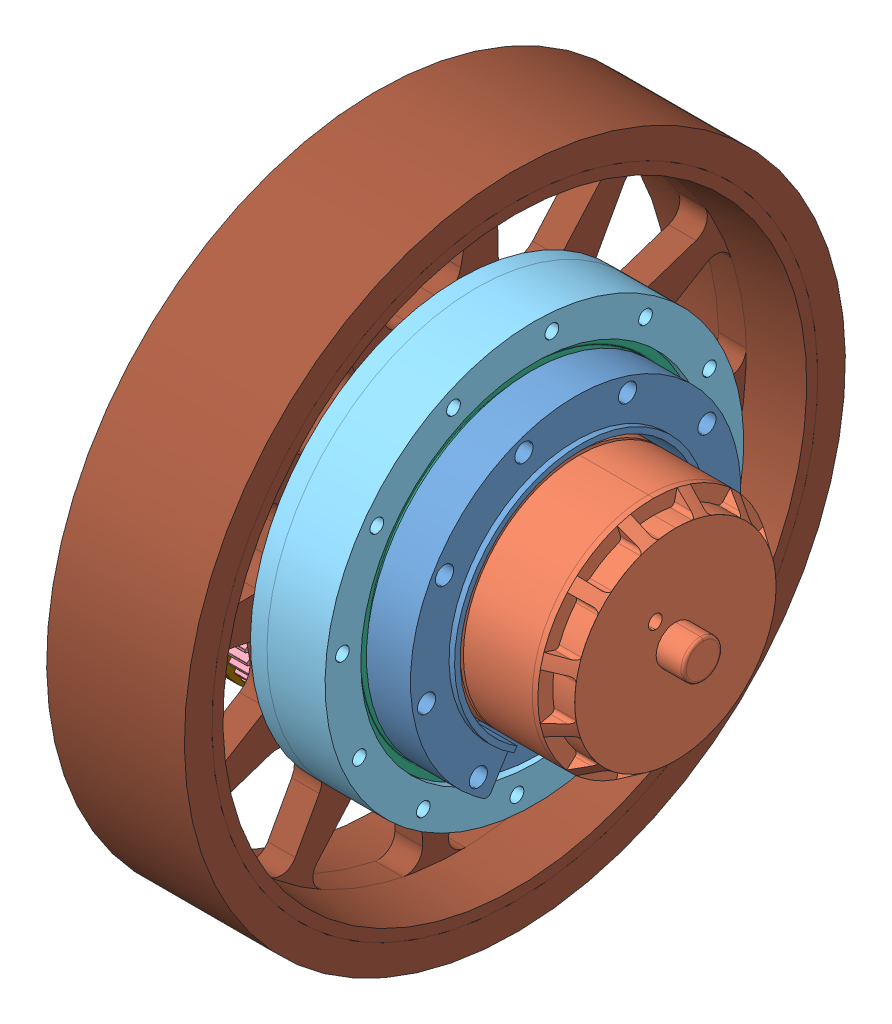
SolidWorks assembly OB ASM改, configuration 默认. Lengths in mm.
Overall size (62.1 167.23 167.23).
25 component instances, 11 part files, 67 mates.
Components (placement in the parent):
- M01改-1: M01改 [默认] at (-15.2454 0 0) x (-1 0 0) z (0 1 0) size (37 60 60)
- RoboMaster M3508改-1: RoboMaster M3508改 [默认] at (23.1956 -8.7166 -16.154) x (0 -0.922142 0.386852) z (-1 0 0) size (42 44.97 43.4)
- GEAR01改-1: GEAR01改 [默认] at (-50.0454 0 0) x (0 0.247551 -0.968875) z (1 0 0) size (10.24 10.24 22.5)
- GEAR02改-1: GEAR02改 [默认] at (-49.2454 18.15 0) x (0 0.099251 -0.995062) z (1 0 0) size (28.69 28.68 13)
- GEAR03改-1: GEAR03改 [默认] at (-44.2954 0 0) x (0 -0.817182 0.576379) z (1 0 0) size (76 76 21.55)
- GEAR02改-2: GEAR02改 [默认] at (-49.2454 -9.075 15.7184) x (0 0.812124 0.583485) z (1 0 0) size (28.69 28.68 13)
- GEAR02改-3: GEAR02改 [默认] at (-49.2454 -9.075 -15.7184) x (0 -0.911375 0.411577) z (1 0 0) size (28.69 28.68 13)
- RA5008改-1: RA5008改 [默认] at (-32.2454 0 0) x (0 0.378016 0.925799) z (0 0.925799 -0.378016) size (66 8 66)
- 法兰轴承 4-7-2.5改-1: 法兰轴承 4-7-2.5改 [默认] at (-35.6454 18.15 0) x (0 0.689337 0.724441) z (0 -0.724441 0.689337) size (8.2 2.5 8.2)
- 法兰轴承 4-7-2.5改-5: 法兰轴承 4-7-2.5改 [默认] at (-49.8454 18.15 0) x (0 0.329942 0.944001) z (0 0.944001 -0.329942) size (8.2 2.5 8.2)
- 法兰轴承 4-7-2.5改-3: 法兰轴承 4-7-2.5改 [默认] at (-35.6454 -9.075 15.7184) x (0 -0.972053 0.234763) z (0 -0.234763 -0.972053) size (8.2 2.5 8.2)
- 法兰轴承 4-7-2.5改-4: 法兰轴承 4-7-2.5改 [默认] at (-35.6454 -9.075 -15.7184) x (0 0.282715 -0.959204) z (0 0.959204 0.282715) size (8.2 2.5 8.2)
- 法兰轴承 4-7-2.5改-6: 法兰轴承 4-7-2.5改 [默认] at (-49.8454 -9.075 15.7184) x (0 -0.9825 -0.186263) z (0 -0.186263 0.9825) size (8.2 2.5 8.2)
- 法兰轴承 4-7-2.5改-7: 法兰轴承 4-7-2.5改 [默认] at (-49.8454 -9.075 -15.7184) x (0 0.652558 -0.757738) z (0 -0.757738 -0.652558) size (8.2 2.5 8.2)
- 4-6-0.2不锈钢垫圈改-1: 4-6-0.2不锈钢垫圈改 [默认] at (-35.6454 18.15 0) x (0 0.139017 -0.99029) z (1 0 0) size (6 6 0.2)
- 4-6-0.2不锈钢垫圈改-7: 4-6-0.2不锈钢垫圈改 [默认] at (-50.0454 18.15 0) x (0 0.139017 -0.99029) z (1 0 0) size (6 6 0.2)
- 4-6-0.2不锈钢垫圈改-8: 4-6-0.2不锈钢垫圈改 [默认] at (-50.0454 -9.075 15.7184) x (0 0.788108 0.615537) z (1 0 0) size (6 6 0.2)
- 4-6-0.2不锈钢垫圈改-9: 4-6-0.2不锈钢垫圈改 [默认] at (-50.0454 -9.075 -15.7184) x (0 -0.927125 0.374753) z (1 0 0) size (6 6 0.2)
- 4-6-0.2不锈钢垫圈改-5: 4-6-0.2不锈钢垫圈改 [默认] at (-35.6454 -9.075 15.7184) x (0 0.788108 0.615537) z (1 0 0) size (6 6 0.2)
- 4-6-0.2不锈钢垫圈改-6: 4-6-0.2不锈钢垫圈改 [默认] at (-35.6454 -9.075 -15.7184) x (0 -0.927125 0.374753) z (1 0 0) size (6 6 0.2)
- P01改-1: P01改 [默认] at (-50.2454 0 0) x (0 0 1) z (-1 0 0) size (61.44 57.23 4)
- M02改-1: M02改 [默认] at (-27.2454 18.15 0) x (0 -0.045999 0.998941) z (-1 0 0) size (4 4 26)
- WHEEL改-1: WHEEL改 [步兵] at (-38.7954 0 0) x (1 0 0) z (0 -0.576379 -0.817182) size (25 120 120)
- M02改-2: M02改 [默认] at (-27.2454 -9.075 15.7184) x (0 -0.842109 -0.539307) z (-1 0 0) size (4 4 26)
- M02改-3: M02改 [默认] at (-27.2454 -9.075 -15.7184) x (0 0.888108 -0.459634) z (-1 0 0) size (4 4 26)
Mates (geometry in assembly coordinates):
- 重合1: coincident aligned: plane of M01改-1 through (-15.2454 0 0) normal (0 1 0)
- 重合2: coincident aligned: plane of M01改-1 through (-15.2454 0 0) normal (0 0 1)
- 重合3: coincident anti-aligned: plane of M01改-1 through (-27.2454 0 21.25) normal (1 0 0); plane of RoboMaster M3508-1 through (-27.2454 0 0) normal (-1 0 0)
- 同心1: concentric anti-aligned: cylinder of M01改-1 through (-15.2454 0 0) axis (1 0 0) radius 21.25; cylinder of RoboMaster M3508-1 through (-25.2454 0 0) axis (-1 0 0) radius 21
- 同心2: concentric anti-aligned: cylinder of RoboMaster M3508-1 through (-35.5454 0 0) axis (1 0 0) radius 2.5; cylinder of GEAR01-1 through (-27.5454 0 0) axis (-1 0 0) radius 2.485
- 同心3: concentric aligned: cylinder of M01改-1 through (-14.2454 18.15 0) axis (-1 0 0) radius 2; cylinder of GEAR02-1 through (-36.2454 18.15 0) axis (-1 0 0) radius 3.5
- 距离1: distance = 1 mm anti-aligned: plane of M01改-1 through (-35.2454 18.15 0) normal (-1 0 0); plane of GEAR02-1 through (-36.2454 14.8652 -4.9696) normal (1 0 0)
- 同心4: concentric anti-aligned: cylinder of M01改-1 through (-15.2454 0 0) axis (1 0 0) radius 22.5; cylinder of GEAR03改-1 through (-36.2954 0 0) axis (-1 0 0) radius 27.5
- 齿轮配合1: gear = 12 : 39 mm: cylinder of GEAR02-1 through (-36.2454 18.15 0) axis (-1 0 0) radius 3.5; cylinder of GEAR01-1 through (-27.5454 0 0) axis (-1 0 0) radius 2.485
- 齿轮配合2: gear = 2340 : 168 mm: cylinder of GEAR01-1 through (-27.5454 0 0) axis (-1 0 0) radius 2.485; cylinder of GEAR03改-1 through (-36.2954 0 0) axis (-1 0 0) radius 27.5
- 重合10: coincident anti-aligned: plane of M01改-1 through (-24.2454 0 24.975) normal (-1 0 0); plane of RA5008改-1 through (-24.2454 -10.5089 -25.7372) normal (1 0 0)
- 同心7: concentric anti-aligned: cylinder of M01改-1 through (-15.2454 0 0) axis (1 0 0) radius 24.975; cylinder of RA5008改-1 through (-32.2454 0 0) axis (-1 0 0) radius 25
- 同心8: concentric anti-aligned: cylinder of M01-1 through (-15.2454 0 0) axis (1 0 0) radius 23.525; cylinder of WZ-200-1 through (-32.2954 0 0) axis (-1 0 0) radius 23.345
- 重合11: coincident anti-aligned: plane of M01-1 through (-33.8654 0 23.525) normal (1 0 0); plane of WZ-200-1 through (-33.8654 0 0) normal (-1 0 0)
- 同心9: concentric anti-aligned: cylinder of M01改-1 through (-51.2454 0 -17.5) axis (1 0 0) radius 1.6; cylinder of RoboMaster M3508-1 through (-27.2454 0 -17.5) axis (-1 0 0) radius 1.5
- 重合12: coincident anti-aligned: plane of GEAR02-1 through (-36.2454 14.8652 -4.9696) normal (1 0 0); plane of 法兰轴承 4-7-2.5-1 through (-36.2454 18.15 0) normal (-1 0 0)
- 同心10: concentric anti-aligned: cylinder of GEAR02-1 through (-36.2454 18.15 0) axis (-1 0 0) radius 3.5; cylinder of 法兰轴承 4-7-2.5-1 through (-35.6454 18.15 0) axis (1 0 0) radius 3.5
- 重合13: coincident anti-aligned: plane of GEAR02-1 through (-49.2454 32.4291 1.4243) normal (-1 0 0); plane of 法兰轴承 4-7-2.5-2 through (-49.2454 18.15 0) normal (1 0 0)
- 同心11: concentric aligned: cylinder of GEAR02-1 through (-36.2454 18.15 0) axis (-1 0 0) radius 3.5; cylinder of 法兰轴承 4-7-2.5-2 through (-49.8454 18.15 0) axis (-1 0 0) radius 3.5
- 重合14: coincident anti-aligned: plane of 法兰轴承 4-7-2.5-1 through (-35.6454 18.15 0) normal (1 0 0); plane of 4-6-0.2不锈钢垫圈-1 through (-35.6454 18.15 0) normal (-1 0 0)
- 同心12: concentric anti-aligned: cylinder of 法兰轴承 4-7-2.5-1 through (-35.6454 18.15 0) axis (1 0 0) radius 4.1; cylinder of 4-6-0.2不锈钢垫圈-1 through (-35.4454 18.15 0) axis (-1 0 0) radius 3
- 重合15: coincident anti-aligned: plane of 法兰轴承 4-7-2.5-2 through (-49.8454 18.15 0) normal (-1 0 0); plane of 4-6-0.2不锈钢垫圈-2 through (-49.8454 18.15 0) normal (1 0 0)
- 同心13: concentric aligned: cylinder of 法兰轴承 4-7-2.5-2 through (-49.8454 18.15 0) axis (-1 0 0) radius 2; cylinder of 4-6-0.2不锈钢垫圈-2 through (-49.8454 18.15 0) axis (-1 0 0) radius 2
- 重合16: coincident anti-aligned: plane of M01改-1 through (-50.2454 0 15) normal (-1 0 0); plane of P01改-1 through (-50.2454 0 0) normal (1 0 0)
- 同心15: concentric aligned: cylinder of M01改-1 through (-15.2454 0 0) axis (1 0 0) radius 21.5; cylinder of P01-1 through (-53.2454 0 0) axis (1 0 0) radius 21.5
- 同心16: concentric anti-aligned: cylinder of M01改-1 through (-14.2454 9.5 16.4545) axis (-1 0 0) radius 1.25; cylinder of P01改-1 through (-53.2454 9.5 16.4545) axis (1 0 0) radius 1.6
- 重合17: coincident anti-aligned: plane of 法兰轴承 5-10-4-1 through (-53.2454 0 0) normal (1 0 0); plane of P01改-1 through (-53.2454 0 0) normal (-1 0 0)
- 重合19: coincident anti-aligned: plane of GEAR03改-1 through (-36.2954 -31.0529 21.9024) normal (-1 0 0); plane of WHEEL改-1 through (-36.2954 -42.4935 29.9717) normal (1 0 0)
- 同心19: concentric anti-aligned: cylinder of GEAR03改-1 through (-22.7454 -28.6014 20.1733) axis (-1 0 0) radius 1.6; cylinder of WHEEL改-1 through (-51.2954 -28.6014 20.1733) axis (1 0 0) radius 1.6
- 同心20: concentric anti-aligned: cylinder of GEAR03改-1 through (-44.2954 0 0) axis (-1 0 0) radius 31; cylinder of WHEEL-1 through (-38.7954 0 0) axis (1 0 0) radius 31.05
- 距离3: distance = 8 mm anti-aligned: plane of RoboMaster M3508-1 through (-35.5454 0 0) normal (-1 0 0); plane of GEAR01-1 through (-27.5454 0 0) normal (1 0 0)
- 重合20: coincident anti-aligned: plane of RoboMaster M3508-1 through (-27.2454 0 0) normal (-1 0 0); plane of M02-1 through (-27.2454 18.15 0) normal (1 0 0)
- 同心21: concentric aligned: cylinder of P01改-1 through (-53.2454 18.15 0) axis (1 0 0) radius 2; cylinder of M02-1 through (-53.2454 18.15 0) axis (1 0 0) radius 2
- 重合21: coincident anti-aligned: plane of GEAR03改-1 through (-36.2954 -31.0529 21.9024) normal (-1 0 0); plane of ASM-1/侧板-1 through (-34.5954 29.6416 23.7776) normal (1 0 0)
- 同心22: concentric anti-aligned: cylinder of GEAR03改-1 through (-22.7454 -28.6014 20.1733) axis (-1 0 0) radius 1.25; cylinder of ASM-1/侧板-1 through (-57.0954 32.1511 -12.5123) axis (1 0 0) radius 1.6
- 同心23: concentric aligned: cylinder of GEAR03改-1 through (-44.2954 0 0) axis (-1 0 0) radius 38; cylinder of ASM-1/侧板-1 through (-37.0954 0 0) axis (-1 0 0) radius 38
- 同心24: concentric anti-aligned: cylinder of GEAR01-1 through (-53.5454 0 0) axis (1 0 0) radius 2.5; cylinder of 法兰轴承 5-10-4-1 through (-54.2454 0 0) axis (-1 0 0) radius 2.5
- 重合25: coincident anti-aligned: plane of GEAR03改-1 through (-24.2454 -25.7617 18.1703) normal (-1 0 0); plane of RA5008改-1 through (-24.2454 -12.4745 -30.5514) normal (1 0 0)
- 重合26: coincident anti-aligned: plane of M01改-1 through (-27.2454 0 -21.25) normal (1 0 0); plane of RoboMaster M3508改-1 through (-27.2454 0 0) normal (-1 0 0)
- 同心25: concentric anti-aligned: cylinder of M01改-1 through (-15.2454 0 0) axis (1 0 0) radius 21.25; cylinder of RoboMaster M3508改-1 through (-25.2454 0 0) axis (-1 0 0) radius 21
- 同心26: concentric anti-aligned: cylinder of RoboMaster M3508改-1 through (-35.5454 0 0) axis (1 0 0) radius 2.5; cylinder of GEAR01改-1 through (-27.5454 0 0) axis (-1 0 0) radius 2.485
- 同心27: concentric aligned: cylinder of M01改-1 through (-14.2454 18.15 0) axis (-1 0 0) radius 2; cylinder of GEAR02改-1 through (-36.2454 18.15 0) axis (-1 0 0) radius 3.5
- 距离4: distance = 1 mm anti-aligned: plane of M01改-1 through (-35.2454 18.15 0) normal (-1 0 0); plane of GEAR02改-1 through (-36.2454 14.8652 4.9696) normal (1 0 0)
- 同心28: concentric: cylinder of ? through (-15.2454 0 0) axis (1 0 0) radius 22.5; cylinder of ? through (-36.2954 0 0) axis (-1 0 0) radius 27.5
- 齿轮配合3: gear = 12 : 39 mm: cylinder of GEAR02改-1 through (-36.2454 18.15 0) axis (-1 0 0) radius 3.5; cylinder of GEAR01改-1 through (-27.5454 0 0) axis (-1 0 0) radius 2.485
- 齿轮配合4: gear = 2340 : 168 mm: cylinder of GEAR01改-1 through (-27.5454 0 0) axis (-1 0 0) radius 2.485; cylinder of GEAR03改-1 through (-36.2954 0 0) axis (-1 0 0) radius 27.5
- 重合27: coincident anti-aligned: plane of M01改-1 through (-24.2454 0 -24.975) normal (-1 0 0); plane of RA5008改-1 through (-24.2454 -10.5089 25.7372) normal (1 0 0)
- 同心29: concentric anti-aligned: cylinder of M01改-1 through (-15.2454 0 0) axis (1 0 0) radius 24.975; cylinder of RA5008改-1 through (-32.2454 0 0) axis (-1 0 0) radius 25
- 同心30: concentric anti-aligned: cylinder of M01改-1 through (-51.2454 0 17.5) axis (1 0 0) radius 1.6; cylinder of RoboMaster M3508改-1 through (-27.2454 0 17.5) axis (-1 0 0) radius 1.5
- 重合28: coincident anti-aligned: plane of GEAR02改-1 through (-36.2454 14.8652 4.9696) normal (1 0 0); plane of 法兰轴承 4-7-2.5改-1 through (-36.2454 18.15 0) normal (-1 0 0)
- 同心31: concentric anti-aligned: cylinder of GEAR02改-1 through (-36.2454 18.15 0) axis (-1 0 0) radius 3.5; cylinder of 法兰轴承 4-7-2.5改-1 through (-35.6454 18.15 0) axis (1 0 0) radius 3.5
- 重合29: coincident anti-aligned: plane of GEAR02改-1 through (-49.2454 32.4291 -1.4243) normal (-1 0 0); plane of 法兰轴承 4-7-2.5改-5 through (-49.2454 18.15 0) normal (1 0 0)
- 同心32: concentric aligned: cylinder of GEAR02改-1 through (-36.2454 18.15 0) axis (-1 0 0) radius 3.5; cylinder of 法兰轴承 4-7-2.5改-5 through (-49.8454 18.15 0) axis (-1 0 0) radius 3.5
- 重合30: coincident anti-aligned: plane of 法兰轴承 4-7-2.5改-1 through (-35.6454 18.15 0) normal (1 0 0); plane of 4-6-0.2不锈钢垫圈改-1 through (-35.6454 18.15 0) normal (-1 0 0)
- 同心33: concentric anti-aligned: cylinder of 法兰轴承 4-7-2.5改-1 through (-35.6454 18.15 0) axis (1 0 0) radius 4.1; cylinder of 4-6-0.2不锈钢垫圈改-1 through (-35.4454 18.15 0) axis (-1 0 0) radius 3
- 重合31: coincident anti-aligned: plane of 法兰轴承 4-7-2.5改-5 through (-49.8454 18.15 0) normal (-1 0 0); plane of 4-6-0.2不锈钢垫圈改-7 through (-49.8454 18.15 0) normal (1 0 0)
- 同心34: concentric aligned: cylinder of 法兰轴承 4-7-2.5改-5 through (-49.8454 18.15 0) axis (-1 0 0) radius 2; cylinder of 4-6-0.2不锈钢垫圈改-7 through (-49.8454 18.15 0) axis (-1 0 0) radius 2
- 重合32: coincident: plane of ? through (-50.2454 0 -15) normal (-1 0 0); plane of ? through (-50.2454 0 0) normal (1 0 0)
- 同心35: concentric: cylinder of ? through (-15.2454 0 0) axis (1 0 0) radius 21.5; cylinder of ? through (-53.2454 0 0) axis (1 0 0) radius 21.5
- 同心36: concentric anti-aligned: cylinder of M01改-1 through (-14.2454 9.5 -16.4545) axis (-1 0 0) radius 1.25; cylinder of P01改-1 through (-53.2454 9.5 -16.4545) axis (1 0 0) radius 1.6
- 重合33: coincident anti-aligned: plane of GEAR03改-1 through (-36.2954 -31.0529 -21.9024) normal (-1 0 0); plane of WHEEL改-1 through (-36.2954 -42.4935 -29.9717) normal (1 0 0)
- 同心37: concentric anti-aligned: cylinder of GEAR03改-1 through (-22.7454 -28.6014 -20.1733) axis (-1 0 0) radius 1.6; cylinder of WHEEL改-1 through (-51.2954 -28.6014 -20.1733) axis (1 0 0) radius 1.6
- 同心38: concentric anti-aligned: cylinder of ? through (-44.2954 0 0) axis (-1 0 0) radius 31; cylinder of ? through (-38.7954 0 0) axis (1 0 0) radius 31.05
- 距离5: distance = 8 mm anti-aligned: plane of RoboMaster M3508改-1 through (-35.5454 0 0) normal (-1 0 0); plane of GEAR01改-1 through (-27.5454 0 0) normal (1 0 0)
- 重合34: coincident anti-aligned: plane of RoboMaster M3508改-1 through (-27.2454 0 0) normal (-1 0 0); plane of M02改-1 through (-27.2454 18.15 0) normal (1 0 0)
- 同心39: concentric aligned: cylinder of P01改-1 through (-53.2454 18.15 0) axis (1 0 0) radius 2; cylinder of M02改-1 through (-53.2454 18.15 0) axis (1 0 0) radius 2
- 重合35: coincident anti-aligned: plane of GEAR03改-1 through (-24.2454 -25.7617 -18.1703) normal (-1 0 0); plane of RA5008改-1 through (-24.2454 -12.4745 30.5514) normal (1 0 0)
